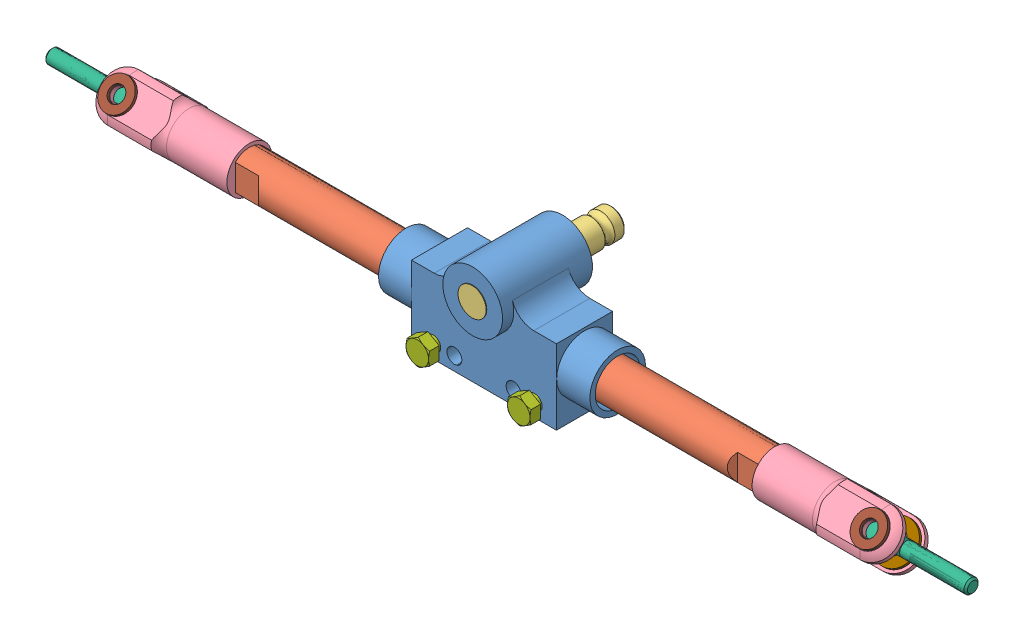
SolidWorks assembly SteeringRackAssy, configuration Default. Lengths in mm.
Overall size (519.26 64.11 81.07).
26 component instances, 11 part files, 41 mates.
Components (placement in the parent):
- SteeringRack-5: SteeringRack [Default] at origin size (296 62.5 80.5)
  - SteeringRackCasting-1: SteeringRackCasting [Default] at (-167.3912 -210.4134 -15.8) size (131.76 62.5 52.7)
  - SteeringRackGear-1: SteeringRackGear [Default] at origin size (296 21.6 21.6)
  - SteeringPinionGear-1: SteeringPinionGear [Default] at (0 20.65 22.5) x (0 0 -1) z (1 0 0) size (172.28 15.88 15.88)
- SteeringRackExt-1: SteeringRackExt [Default] at (148 0 0) x (0 0.731354 -0.681998) z (1 0 0) size (25.4 26.5 76.7)
- SteeringRackExt-2: SteeringRackExt [Default] at (-148 0 0) x (0 -0.731354 0.681998) z (-1 0 0) size (25.4 26.5 76.7)
- RodEnd312Male-1: RodEnd312Male [Default] at (212 0 0) x (0 -0.697771 -0.716321) z (0 0.716321 -0.697771) size (22.23 58.75 22.2)
  - RodEndBall312-1: RodEndBall312 [Default] at origin size (15.06 15.06 22.2)
  - RodEndRace312Male-1: RodEndRace312Male [Default] at origin size (22.23 58.75 7.94)
- RodEnd312Male-2: RodEnd312Male [Default] at (-212 0 0) x (0 0.726824 0.686823) z (0 0.686823 -0.726824) size (22.23 58.75 22.2)
  - RodEndBall312-1: RodEndBall312 [Default] at origin size (15.06 15.06 22.2)
  - RodEndRace312Male-1: RodEndRace312Male [Default] at origin size (22.23 58.75 7.94)
- Hex Bolt_AI-1: Hex Bolt_AI [HBOLT 0.3125-24x1.75x0.875-N] at (-28.575 -17.4 24.769) x (0 0 -1) z (1 0 0) size (50.42 14.66 12.7)
- Hex Bolt_AI-2: Hex Bolt_AI [HBOLT 0.3125-24x1.75x0.875-N] at (28.575 -17.4 24.769) x (0 0 -1) z (1 0 0) size (50.42 14.66 12.7)
- Socket Head Cap Screw_AI-1: Socket Head Cap Screw_AI [HX-SHCS 0.375-24x1x1-N] at (-165.525 0 0) x (1 0 0) z (0 0.782519 0.622627) size (34.92 14.29 14.29)
- Socket Head Cap Screw_AI-2: Socket Head Cap Screw_AI [HX-SHCS 0.375-24x1x1-N] at (165.525 0 0) x (-1 0 0) z (0 0.838328 0.545166) size (34.92 14.29 14.29)
- Flat Washer Type B Regular_AI-1: Flat Washer Type B Regular_AI [Regular FW 0.3125] at (212 -4.9445 -5.3023) x (0 -0.681998 -0.731354) z (-0.681998 -0.534878 0.498782) size (1.6 22.23 22.23)
- Flat Washer Type B Regular_AI-2: Flat Washer Type B Regular_AI [Regular FW 0.3125] at (212 4.9445 5.3023) x (0 0.681998 0.731354) z (0.681998 -0.534878 0.498782) size (1.6 22.23 22.23)
- Flat Washer Type B Regular_AI-3: Flat Washer Type B Regular_AI [Regular FW 0.3125] at (-212 4.9445 5.3023) x (0 0.681998 0.731354) z (0.681998 -0.534878 0.498782) size (1.6 22.23 22.23)
- Flat Washer Type B Regular_AI-4: Flat Washer Type B Regular_AI [Regular FW 0.3125] at (-212 -4.9445 -5.3023) x (0 -0.681998 -0.731354) z (-0.681998 -0.534878 0.498782) size (1.6 22.23 22.23)
- Hex Nut_AI-3: Hex Nut_AI [HNUT 0.3125-24-D-N] at (28.575 -17.4 -25.7342) x (0.923728 0.383049 0) z (0 0 -1) size (12.7 14.66 6.93)
- Hex Nut_AI-4: Hex Nut_AI [HNUT 0.3125-24-D-N] at (-28.575 -17.4 -25.7342) x (0.923728 0.383049 0) z (0 0 -1) size (12.7 14.66 6.93)
- Flat Washer Type A Narrow_AI-1: Flat Washer Type A Narrow_AI [Preferred Narrow FW 0.3125] at (-212 -9.0365 -9.6904) x (0 0.681998 0.731354) z (-0.731354 -0.498782 0.465122) size (1.65 17.48 17.48)
- Flat Washer Type A Narrow_AI-2: Flat Washer Type A Narrow_AI [Preferred Narrow FW 0.3125] at (-212 9.0365 9.6904) x (0 -0.681998 -0.731354) z (0.731354 -0.498782 0.465122) size (1.65 17.48 17.48)
- Flat Washer Type A Narrow_AI-3: Flat Washer Type A Narrow_AI [Preferred Narrow FW 0.3125] at (212 -9.0365 -9.6904) x (0 0.681998 0.731354) z (-0.731354 -0.498782 0.465122) size (1.65 17.48 17.48)
- Flat Washer Type A Narrow_AI-4: Flat Washer Type A Narrow_AI [Preferred Narrow FW 0.3125] at (212 9.0365 9.6904) x (0 -0.681998 -0.731354) z (0.731354 -0.498782 0.465122) size (1.65 17.48 17.48)
Mates (geometry in assembly coordinates):
- Coincident6: coincident: plane of assembly; plane of assembly; plane of SteeringRackExt-1 through (148 0 0) normal (0 0.681998 0.731354); plane of SteeringRackExt-2 through (-148 0 0) normal (0 0.681998 0.731354)
- Coincident8: coincident: point of RodEnd312Male-1/RodEndBall312-1; point of SteeringRackExt-1
- Coincident9: coincident: point of RodEnd312Male-2/RodEndBall312-1; point of SteeringRackExt-2
- Coincident10: coincident: plane of assembly through (0 0 0) normal (1 0 0); plane of SteeringRack-5/SteeringRackCasting-1 through (0 -210.4134 -15.8) normal (1 0 0); plane of assembly
- Concentric5: concentric: cylinder of assembly; cylinder of assembly; cylinder of SteeringRack-5/SteeringRackCasting-1 through (-28.575 -17.4 22.15) axis (0 0 -1) radius 4.2; cylinder of Hex Bolt_AI-1 through (-28.575 -17.4 24.769) axis (0 0 1) radius 3.9688
- Distance4: distance = 3 mm: plane of assembly; plane of assembly; plane of SteeringRack-5/SteeringRackCasting-1 through (-40.85 -25 15.8) normal (0 0 1); plane of Hex Bolt_AI-1 through (-28.575 -10.0677 18.8) normal (0 0 -1)
- Concentric6: concentric: cylinder of assembly; cylinder of assembly; cylinder of SteeringRack-5/SteeringRackCasting-1 through (28.575 -17.4 22.15) axis (0 0 -1) radius 4.2; cylinder of Hex Bolt_AI-2 through (28.575 -17.4 24.769) axis (0 0 1) radius 3.9688
- Distance5: distance = 3 mm: plane of assembly; plane of assembly; plane of SteeringRack-5/SteeringRackCasting-1 through (-40.85 -25 15.8) normal (0 0 1); plane of Hex Bolt_AI-2 through (28.575 -10.0677 18.8) normal (0 0 -1)
- Concentric7: concentric: cylinder of assembly; cylinder of assembly; cylinder of SteeringRackExt-2 through (-148 0 0) axis (-1 0 0) radius 5; cylinder of Socket Head Cap Screw_AI-1 through (-197.275 0 0) axis (-1 0 0) radius 7.1437
- Coincident13: coincident: plane of assembly; plane of assembly; plane of SteeringRackExt-2 through (-156 0 0) normal (-1 0 0); plane of Socket Head Cap Screw_AI-1 through (-156 4.4479 -5.5901) normal (1 0 0)
- Concentric8: concentric: cylinder of assembly; cylinder of assembly; cylinder of SteeringRackExt-1 through (148 0 0) axis (1 0 0) radius 5; cylinder of Socket Head Cap Screw_AI-2 through (197.275 0 0) axis (1 0 0) radius 7.1437
- Coincident14: coincident: plane of SteeringRackExt-1 through (156 0 0) normal (1 0 0); plane of Socket Head Cap Screw_AI-2 through (156 -3.8945 5.9888) normal (-1 0 0)
- Coincident15: coincident: plane of assembly through (0 0 0) normal (1 0 0); plane of SteeringRack-5/SteeringRackCasting-1 through (0 -210.4134 -15.8) normal (1 0 0); plane of assembly
- Parallel1: parallel: plane of SteeringRack-5/SteeringRackGear-1 through (0 0 0) normal (0 0 1); plane of assembly through (0 0 0) normal (0 0 1)
- Angle1: planar angle = 0.750492 rad: plane of assembly through (0 0 0) normal (0 0 1); plane of SteeringRackExt-1 through (254.9 -14.2327 3.3591) normal (0 0.681998 0.731354); plane of assembly
- Concentric9: concentric: cylinder of assembly; cylinder of assembly; cylinder of SteeringRackExt-1 through (212 -12.8898 -13.8226) axis (0 0.681998 0.731354) radius 4.1021; cylinder of Flat Washer Type B Regular_AI-1 through (212 18.8743 20.2402) axis (0 0.681998 0.731354) radius 4.3688
- Coincident20: coincident: plane of SteeringRackExt-1 through (254.9 -14.2327 3.3591) normal (0 0.681998 0.731354); plane of Flat Washer Type B Regular_AI-1 through (215.1951 -7.1236 -3.2703) normal (0 -0.681998 -0.731354)
- Concentric10: concentric: cylinder of assembly; cylinder of assembly; cylinder of SteeringRackExt-1 through (212 -12.8898 -13.8226) axis (0 0.681998 0.731354) radius 4.1021; cylinder of Flat Washer Type B Regular_AI-2 through (212 -18.8743 -20.2402) axis (0 -0.681998 -0.731354) radius 4.3688
- Coincident21: coincident: plane of SteeringRackExt-1 through (254.9 -4.3437 13.9637) normal (0 -0.681998 -0.731354); plane of Flat Washer Type B Regular_AI-2 through (208.8049 2.7654 7.3343) normal (0 0.681998 0.731354)
- Concentric11: concentric: cylinder of assembly; cylinder of assembly; cylinder of SteeringRackExt-2 through (-212 -12.8898 -13.8226) axis (0 0.681998 0.731354) radius 4.1021; cylinder of Flat Washer Type B Regular_AI-3 through (-212 -18.8743 -20.2402) axis (0 -0.681998 -0.731354) radius 4.3688
- Coincident22: coincident: plane of SteeringRackExt-2 through (-254.9 14.2327 -3.3591) normal (0 -0.681998 -0.731354); plane of Flat Washer Type B Regular_AI-3 through (-215.1951 2.7654 7.3343) normal (0 0.681998 0.731354)
- Concentric12: concentric: cylinder of assembly; cylinder of assembly; cylinder of SteeringRackExt-2 through (-212 -12.8898 -13.8226) axis (0 0.681998 0.731354) radius 4.1021; cylinder of Flat Washer Type B Regular_AI-4 through (-212 18.8743 20.2402) axis (0 0.681998 0.731354) radius 4.3688
- Coincident23: coincident: plane of SteeringRackExt-2 through (-254.9 4.3437 -13.9637) normal (0 0.681998 0.731354); plane of Flat Washer Type B Regular_AI-4 through (-208.8049 -7.1236 -3.2703) normal (0 -0.681998 -0.731354)
- Coincident24: coincident: plane of SteeringRack-5/SteeringRackGear-1 through (0 0 0) normal (0 0 1); plane of assembly through (0 0 0) normal (0 0 1)
- Coincident25: coincident: plane of SteeringRack-5/SteeringRackGear-1 through (0 0 0) normal (0 1 0); plane of assembly through (0 0 0) normal (0 1 0)
- Concentric15: concentric: cylinder of assembly; cylinder of assembly; cylinder of SteeringRackExt-1 through (238 0 0) axis (-1 0 0) radius 12.7; cylinder of SteeringRack-5/SteeringRackGear-1 through (-180.4724 0 0) axis (-1 0 0) radius 10.8
- Coincident26: coincident: plane of SteeringRack-5/SteeringRackGear-1 through (148 10.8 0) normal (1 0 0); plane of SteeringRackExt-1 through (148 0 0) normal (-1 0 0)
- Concentric16: concentric: cylinder of SteeringRackExt-2 through (-238 0 0) axis (1 0 0) radius 12.7; cylinder of SteeringRack-5/SteeringRackGear-1 through (-180.4724 0 0) axis (-1 0 0) radius 10.8
- Coincident27: coincident: plane of SteeringRack-5/SteeringRackGear-1 through (-148 10.8 0) normal (-1 0 0); plane of SteeringRackExt-2 through (-148 0 0) normal (1 0 0)
- Concentric17: concentric: cylinder of assembly; cylinder of assembly; cylinder of Hex Bolt_AI-2 through (28.575 -17.4 24.769) axis (0 0 1) radius 3.9688; cylinder of Hex Nut_AI-3 through (28.575 -17.4 -0.6967) axis (0 0 -1) radius 3.9688
- Distance6: distance = 3 mm: plane of SteeringRack-5/SteeringRackCasting-1 through (-40.85 -25 -15.8) normal (0 0 -1); plane of Hex Nut_AI-3 through (31.3836 -24.1731 -18.8) normal (0 0 1)
- Concentric18: concentric: cylinder of assembly; cylinder of assembly; cylinder of Hex Bolt_AI-1 through (-28.575 -17.4 24.769) axis (0 0 1) radius 3.9688; cylinder of Hex Nut_AI-4 through (-28.575 -17.4 -0.6967) axis (0 0 -1) radius 3.9688
- Distance7: distance = 3 mm: plane of SteeringRack-5/SteeringRackCasting-1 through (-40.85 -25 -15.8) normal (0 0 -1); plane of Hex Nut_AI-4 through (-25.7664 -24.1731 -18.8) normal (0 0 1)
- Concentric19: concentric: cylinder of assembly; cylinder of assembly; cylinder of SteeringRackExt-2 through (-212 -12.8898 -13.8226) axis (0 0.681998 0.731354) radius 4.1021; cylinder of Flat Washer Type A Narrow_AI-1 through (-212 -32.8553 -35.233) axis (0 -0.681998 -0.731354) radius 4.3688
- Coincident28: coincident: plane of SteeringRackExt-2 through (-233.1523 0.2517 -18.3518) normal (0 -0.681998 -0.731354); plane of Flat Washer Type A Narrow_AI-1 through (-214.9795 -6.6997 -11.8695) normal (0 0.681998 0.731354)
- Concentric20: concentric: cylinder of assembly; cylinder of assembly; cylinder of SteeringRackExt-2 through (-212 -12.8898 -13.8226) axis (0 0.681998 0.731354) radius 4.1021; cylinder of Flat Washer Type A Narrow_AI-2 through (-212 32.8553 35.233) axis (0 0.681998 0.731354) radius 4.3688
- Coincident29: coincident: plane of SteeringRackExt-2 through (-233.1523 18.3247 1.0291) normal (0 0.681998 0.731354); plane of Flat Washer Type A Narrow_AI-2 through (-209.0205 11.3733 7.5114) normal (0 -0.681998 -0.731354)
- Concentric21: concentric: cylinder of assembly; cylinder of assembly; cylinder of SteeringRackExt-1 through (212 -12.8898 -13.8226) axis (0 0.681998 0.731354) radius 4.1021; cylinder of Flat Washer Type A Narrow_AI-3 through (212 -32.8553 -35.233) axis (0 -0.681998 -0.731354) radius 4.3688
- Coincident30: coincident: plane of SteeringRackExt-1 through (233.1523 -18.3247 -1.0291) normal (0 -0.681998 -0.731354); plane of Flat Washer Type A Narrow_AI-3 through (209.0205 -6.6997 -11.8695) normal (0 0.681998 0.731354)
- Concentric22: concentric: cylinder of assembly; cylinder of assembly; cylinder of SteeringRackExt-1 through (212 -12.8898 -13.8226) axis (0 0.681998 0.731354) radius 4.1021; cylinder of Flat Washer Type A Narrow_AI-4 through (212 32.8553 35.233) axis (0 0.681998 0.731354) radius 4.3688
- Coincident31: coincident: plane of SteeringRackExt-1 through (233.1523 -0.2517 18.3518) normal (0 0.681998 0.731354); plane of Flat Washer Type A Narrow_AI-4 through (214.9795 11.3733 7.5114) normal (0 -0.681998 -0.731354)
